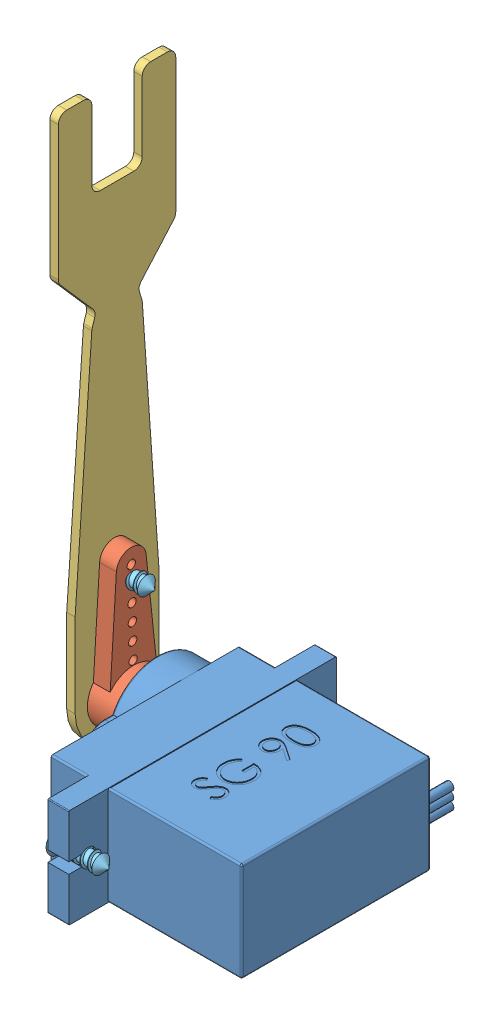
SolidWorks assembly AR1, configuration Predeterminado. Lengths in mm.
Overall size (34.06 68.75 31.9).
7 component instances, 5 part files, 28 mates.
Components (placement in the parent):
- sg90-2: sg90 [Default] at (126.818 -193.0635 98.9775) x (0 0 1) z (0 -1 0) size (31.9 29.9 11.8)
- SG90 plastic Horn-2: SG90 plastic Horn [Default] at (97.368 -198.9635 104.8775) x (0 0.999767 0.021606) z (0 -0.021606 0.999767) size (19.4 4 7.07)
- Arm-2: Arm [Predeterminado] at (94.368 -183.2019 59.6715) x (0 0 1) z (-1 0 0) size (14 67.85 1)
- (M2_3_mm)_90116A007_METRIC 316 SS PAN HEAD PHILLIPS MACHINE SCREW-2: (M2_3_mm)_90116A007_METRIC 316 SS PAN HEAD PHILLIPS MACHINE SCREW [90116A007] at (97.368 -198.9635 104.8775) x (0 0 1) z (-1 0 0) size (4 4 4.68)
- M2x6 SelfTap Screw-1: M2x6 SelfTap Screw [Predeterminado] at (93.868 -186.4635 104.8775) x (0 0.924225 0.381849) z (-1 0 0) size (3.4 3.28 6)
- M2x6 SelfTap Screw-3: M2x6 SelfTap Screw [Predeterminado] at (107.418 -198.9635 123.8775) x (0 0.924225 0.381849) z (-1 0 0) size (3.4 3.28 6)
- M2x6 SelfTap Screw-5: M2x6 SelfTap Screw [Predeterminado] at (107.418 -198.9635 96.5775) x (0 0.924225 0.381849) z (-1 0 0) size (3.4 3.28 6)
Mates (geometry in assembly coordinates):
- Coincidente272: coincident: plane of ? through (205.2764 -198.9635 104.8775) normal (1 0 0); plane of ? through (205.2764 -197.7187 104.8985) normal (-1 0 0)
- Concéntrica139: concentric: circle of ?; circle of ?
- Concéntrica154: concentric: circle of ?; circle of ?
- Distancia47: distance = 1 mm: plane of ? through (194.7764 -198.9635 96.5775) normal (1 0 0); plane of ? through (193.7764 -204.8635 94.2775) normal (1 0 0)
- Concéntrica155: concentric: circle of ?; circle of ?
- Distancia48: distance = 1 mm: plane of ? through (194.7764 -198.9635 123.8775) normal (1 0 0); plane of ? through (193.7764 -193.0635 126.1775) normal (1 0 0)
- Coincidente273: coincident: plane of sg90-2 through (96.918 -198.9635 104.8775) normal (-1 0 0); plane of SG90 plastic Horn-2 through (96.918 -197.7188 104.9044) normal (1 0 0)
- Concéntrica140: concentric: circle of sg90-2; circle of SG90 plastic Horn-2
- Concéntrica156: concentric: circle of sg90-2; circle of M2x6 SelfTap Screw-5
- Distancia49: distance = 1 mm: plane of M2x6 SelfTap Screw-5 through (107.418 -198.9635 96.5775) normal (-1 0 0); plane of sg90-2 through (108.418 -193.0635 94.2775) normal (-1 0 0)
- Concéntrica158: concentric: circle of sg90-2; circle of M2x6 SelfTap Screw-3
- Distancia50: distance = 1 mm: plane of M2x6 SelfTap Screw-3 through (107.418 -198.9635 123.8775) normal (-1 0 0); plane of sg90-2 through (108.418 -204.8635 126.1775) normal (-1 0 0)
- Coincidente275: coincident: plane of ? through (206.8264 -195.429 104.9372) normal (1 0 0); plane of ? through (206.8264 -158.9009 101.2558) normal (-1 0 0)
- Concéntrica143: concentric: circle of ?; circle of ?
- Bloquear1: lock: unknown of ?; unknown of ?
- Coincidente278: coincident: plane of SG90 plastic Horn-2 through (95.368 -195.4293 104.9539) normal (-1 0 0); plane of Arm-2 through (95.368 -158.9009 108.4991) normal (1 0 0)
- Concéntrica144: concentric: circle of SG90 plastic Horn-2; circle of Arm-2
- Bloquear2: lock: unknown of Arm-2; unknown of SG90 plastic Horn-2
- Bloquear3: lock: unknown of Arm-2; unknown of SG90 plastic Horn-2
- Bloquear4: lock: unknown of SG90 plastic Horn-2; unknown of Arm-2
- Coincidente281: coincident: plane of ? through (207.8264 -158.9009 101.2558) normal (1 0 0); plane of ? through (207.8264 -198.9635 104.8775) normal (-1 0 0)
- Concéntrica145: concentric: circle of ?; circle of ?
- Concéntrica148: concentric: circle of ?; circle of ?
- Distancia46: distance = 0.5 mm: plane of ? through (208.3264 -186.4635 104.8775) normal (1 0 0); plane of ? through (207.8264 -158.9009 101.2558) normal (1 0 0)
- Coincidente282: coincident: plane of Arm-2 through (94.368 -158.9009 108.4991) normal (-1 0 0); plane of (M2_3_mm)_90116A007_METRIC 316 SS PAN HEAD PHILLIPS MACHINE SCREW-2 through (94.368 -198.9635 104.8775) normal (1 0 0)
- Concéntrica146: concentric: circle of Arm-2; circle of (M2_3_mm)_90116A007_METRIC 316 SS PAN HEAD PHILLIPS MACHINE SCREW-2
- Concéntrica147: concentric: circle of Arm-2; circle of M2x6 SelfTap Screw-1
- Distancia45: distance = 0.5 mm: plane of M2x6 SelfTap Screw-1 through (93.868 -186.4635 104.8775) normal (-1 0 0); plane of Arm-2 through (94.368 -158.9009 108.4991) normal (-1 0 0)
